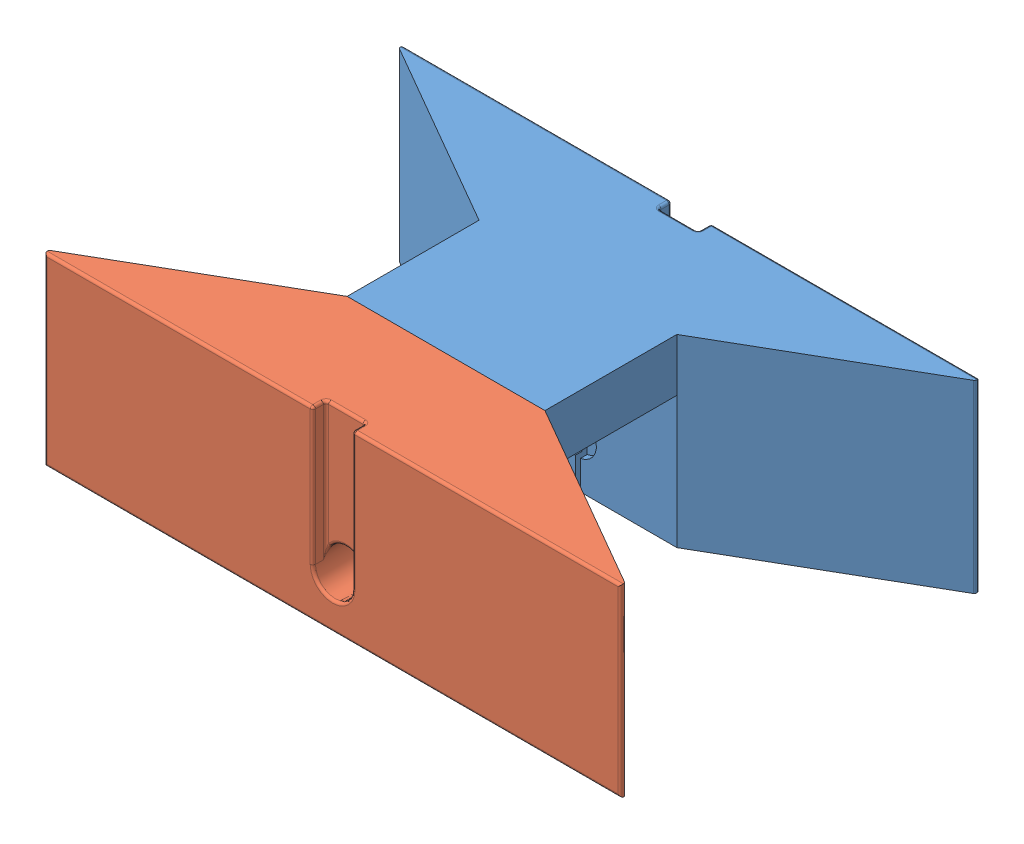
SolidWorks assembly SensorHousing, configuration Default. Lengths in mm.
Overall size (218.49 70 136.08).
2 component instances, 2 part files, 2 mates.
Components (placement in the parent):
- Sensor Block-1: Sensor Block [Default] at (0 0 -136) x (-1 0 0) z (0 0 -1) size (218.49 70 93.08)
- LED Block-1: LED Block [Default] at origin size (218.49 70 43)
Mates (geometry in assembly coordinates):
- Concentric2: concentric anti-aligned: circle of Sensor Block-1; circle of LED Block-1
- Distance2: distance = 50 mm anti-aligned: plane of LED Block-1 through (-37.5 70 -43) normal (0 0 -1); plane of Sensor Block-1 through (37.5 70 -93) normal (0 0 1)
